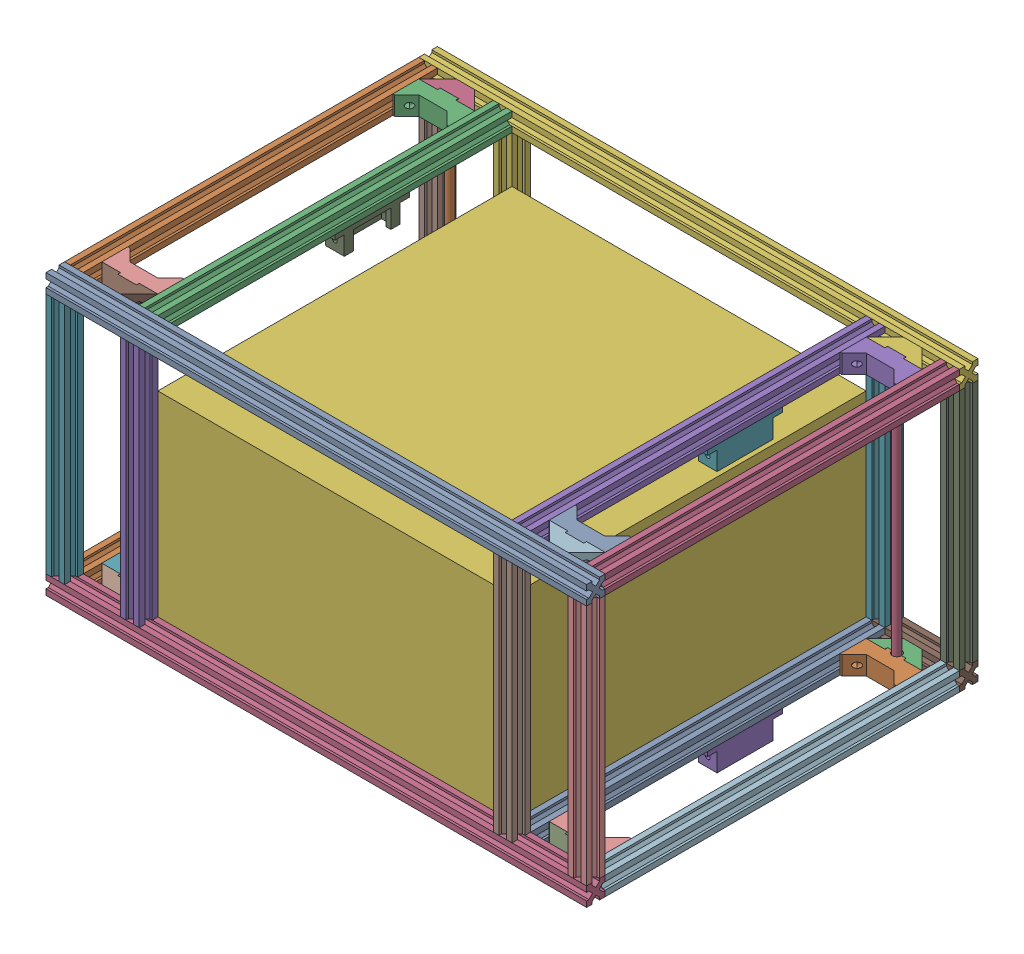
SolidWorks assembly Travelers Gamma 2 caisson av, configuration Défaut. Lengths in mm.
Overall size (580 325 420).
49 component instances, 8 part files, 9 mates.
Components (placement in the parent):
- chassis vide-1: chassis vide [Défaut] at (258.3275 830 354.8864) x (0 0 -1) z (0 -1 0) size (420 580 300)
  - module externe1.0-1: module externe1.0 [Défaut] at origin size (420 580 300)
    - base chassis horizontale-1: base chassis horizontale [Défaut] at (107.5488 34.6411 0) size (420 580 20)
      - profilé 580-1: profilé 580 [Défaut] at (-152.6624 -292.9685 550) size (20 580 20)
      - profilé 380-1: profilé 380 [Défaut] at (-152.6624 -272.9685 550) x (0 0 1) z (0 1 0) size (20 380 20)
      - profilé 380-2: profilé 380 [Défaut] at (227.3376 -212.9685 550) x (0 0 1) z (0 -1 0) size (20 380 20)
      - profilé 380-3: profilé 380 [Défaut] at (227.3376 267.0315 550) x (0 0 1) z (0 -1 0) size (20 380 20)
      - profilé 380-4: profilé 380 [Défaut] at (227.3376 187.0315 550) x (0 0 1) z (0 -1 0) size (20 380 20)
      - profilé 580-2: profilé 580 [Défaut] at (247.3376 -292.9685 530) x (0 0 -1) z (1 0 0) size (20 580 20)
    - profilé 260-1: profilé 260 [Défaut] at (-45.1136 -238.3275 550) x (0 1 0) z (1 0 0) size (20 260 20)
    - profilé 260-2: profilé 260 [Défaut] at (334.8864 -258.3275 810) x (-1 0 0) z (0 -1 0) size (20 260 20)
    - profilé 260-3: profilé 260 [Défaut] at (334.8864 321.6725 550) x (-1 0 0) z (0 1 0) size (20 260 20)
    - profilé 260-4: profilé 260 [Défaut] at (-65.1136 321.6725 550) x (-1 0 0) z (0 1 0) size (20 260 20)
    - base chassis horizontale-2: base chassis horizontale [Défaut] at (182.224 28.704 280) x (-1 0 0) z (0 0 1) size (420 580 20)
      - profilé 580-1: profilé 580 [Défaut] at (-152.6624 -292.9685 550) size (20 580 20)
      - profilé 380-1: profilé 380 [Défaut] at (-152.6624 -272.9685 550) x (0 0 1) z (0 1 0) size (20 380 20)
      - profilé 380-2: profilé 380 [Défaut] at (227.3376 -212.9685 550) x (0 0 1) z (0 -1 0) size (20 380 20)
      - profilé 380-3: profilé 380 [Défaut] at (227.3376 267.0315 550) x (0 0 1) z (0 -1 0) size (20 380 20)
      - profilé 380-4: profilé 380 [Défaut] at (227.3376 187.0315 550) x (0 0 1) z (0 -1 0) size (20 380 20)
      - profilé 580-2: profilé 580 [Défaut] at (247.3376 -292.9685 530) x (0 0 -1) z (1 0 0) size (20 580 20)
    - profilé 260-5: profilé 260 [Défaut] at (-65.1136 -158.3275 550) x (-1 0 0) z (0 1 0) size (20 260 20)
    - profilé 260-6: profilé 260 [Défaut] at (354.8864 -178.3275 550) x (1 0 0) z (0 -1 0) size (20 260 20)
    - profilé 260-7: profilé 260 [Défaut] at (334.8864 221.6725 810) x (-1 0 0) z (0 -1 0) size (20 260 20)
    - profilé 260-8: profilé 260 [Défaut] at (-45.1136 221.6725 810) x (0 -1 0) z (1 0 0) size (20 260 20)
  - fin axe a v2.0-1: fin axe a v2.0 [Défaut] at (-45.1136 301.6725 810) x (0 -1 0) z (0 0 1) size (60 20 20)
  - fin axe b v2.0-1: fin axe b v2.0 [Défaut] at (-25.2136 241.6725 830) x (0 1 0) z (0 0 -1) size (60 30.9 20)
  - axe 8mm 290-5: axe 8mm 290 [Défaut] at (-28.1136 271.6725 535) size (8 8 290)
  - fin axe a v2.0-2: fin axe a v2.0 [Défaut] at (-45.1136 241.6725 550) x (0 1 0) z (0 0 -1) size (60 20 20)
  - fin axe b v2.0-2: fin axe b v2.0 [Défaut] at (-25.2136 301.6725 530) x (0 -1 0) z (0 0 1) size (60 30.9 20)
  - fin axe b v2.0-9: fin axe b v2.0 [Défaut] at (314.9864 301.6725 830) x (0 -1 0) z (0 0 -1) size (60 30.9 20)
  - fin axe a v2.0-9: fin axe a v2.0 [Défaut] at (334.8864 241.6725 810) x (0 1 0) z (0 0 1) size (60 20 20)
  - axe 8mm 290-6: axe 8mm 290 [Défaut] at (317.8864 271.6725 825) x (-1 0 0) z (0 0 -1) size (8 8 290)
  - fin axe b v2.0-10: fin axe b v2.0 [Défaut] at (314.9864 241.6725 530) x (0 1 0) z (0 0 1) size (60 30.9 20)
  - fin axe a v2.0-10: fin axe a v2.0 [Défaut] at (334.8864 301.6725 550) x (0 -1 0) z (0 0 -1) size (60 20 20)
  - fin axe b v2.0-11: fin axe b v2.0 [Défaut] at (-25.2136 -238.3275 830) x (0 1 0) z (0 0 -1) size (60 30.9 20)
  - fin axe a v2.0-11: fin axe a v2.0 [Défaut] at (-45.1136 -178.3275 810) x (0 -1 0) z (0 0 1) size (60 20 20)
  - axe 8mm 290-7: axe 8mm 290 [Défaut] at (-28.1136 -208.3275 825) x (1 0 0) z (0 0 -1) size (8 8 290)
  - fin axe b v2.0-12: fin axe b v2.0 [Défaut] at (-25.2136 -178.3275 530) x (0 -1 0) z (0 0 1) size (60 30.9 20)
  - fin axe a v2.0-12: fin axe a v2.0 [Défaut] at (-45.1136 -238.3275 550) x (0 1 0) z (0 0 -1) size (60 20 20)
  - fin axe b v2.0-13: fin axe b v2.0 [Défaut] at (314.9864 -178.3275 830) x (0 -1 0) z (0 0 -1) size (60 30.9 20)
  - fin axe a v2.0-13: fin axe a v2.0 [Défaut] at (334.8864 -238.3275 810) x (0 1 0) z (0 0 1) size (60 20 20)
  - axe 8mm 290-8: axe 8mm 290 [Défaut] at (317.8864 -208.3275 535) x (-1 0 0) z (0 0 1) size (8 8 290)
  - fin axe b v2.0-14: fin axe b v2.0 [Défaut] at (314.9864 -238.3275 530) x (0 1 0) z (0 0 1) size (60 30.9 20)
  - fin axe a v2.0-14: fin axe a v2.0 [Défaut] at (334.8864 -178.3275 550) x (0 -1 0) z (0 0 -1) size (60 20 20)
- support pivot-1: support pivot [Défaut] at (480.0573 10 140) x (-1 0 0) z (0 0 1) size (20 29.4 80)
- cuve etanche avant courte-1: cuve etanche avant courte [Défaut] at (290 0 210) x (1 0 0) z (0 1 0) size (380 380 230)
- support pivot-2: support pivot [Défaut] at (480.0573 290 140) x (-1 0 0) z (0 0 1) size (20 29.4 80)
- support pivot-3: support pivot [Défaut] at (99.9427 10 200) x (1 0 0) z (0 0 -1) size (20 29.4 80)
- support pivot-4: support pivot [Défaut] at (99.9427 290 200) x (1 0 0) z (0 0 -1) size (20 29.4 80)
Mates (geometry in assembly coordinates):
- Coïncidente1: coincident anti-aligned: plane of chassis vide-1/module externe1.0-1/base chassis horizontale-1/profilé 580-2 through (0 300 0) normal (-1 0 0)
- Coïncidente2: coincident anti-aligned: plane of chassis vide-1/module externe1.0-1/base chassis horizontale-1/profilé 580-2 through (580 300 0) normal (0 0 -1)
- Coïncidente3: coincident anti-aligned: plane of chassis vide-1/fin axe b v2.0-11 through (20 0 380.1) normal (0 -1 0)
- Coïncidente4: coincident aligned: plane of chassis vide-1/module externe1.0-1/base chassis horizontale-2/profilé 380-2 through (500 0 20) normal (1 0 0); plane of support pivot-1 through (500 10 200) normal (1 0 0)
- Coïncidente5: coincident anti-aligned: plane of chassis vide-1/module externe1.0-1/base chassis horizontale-2/profilé 380-2 through (500 0 20) normal (0 -1 0); plane of support pivot-1 through (480.0573 0 200) normal (0 1 0)
- Distance1: distance = 60 mm: point of support pivot-1; unknown of chassis vide-1/module externe1.0-1/base chassis horizontale-2/profilé 380-2
- Coïncidente7: coincident anti-aligned: plane of chassis vide-1/module externe1.0-1/base chassis horizontale-2/profilé 380-2 through (480 0 20) normal (-1 0 0); plane of cuve etanche avant courte-1 through (480 210 20) normal (1 0 0)
- Coïncidente8: coincident anti-aligned: plane of chassis vide-1/module externe1.0-1/base chassis horizontale-2/profilé 580-1 through (0 0 20) normal (0 0 1); plane of cuve etanche avant courte-1 through (100 210 20) normal (0 0 -1)
- Coïncidente9: coincident aligned: plane of chassis vide-1/module externe1.0-1/base chassis horizontale-2/profilé 580-1 through (0 0 20) normal (0 -1 0); plane of cuve etanche avant courte-1 through (290 0 210) normal (0 -1 0)
